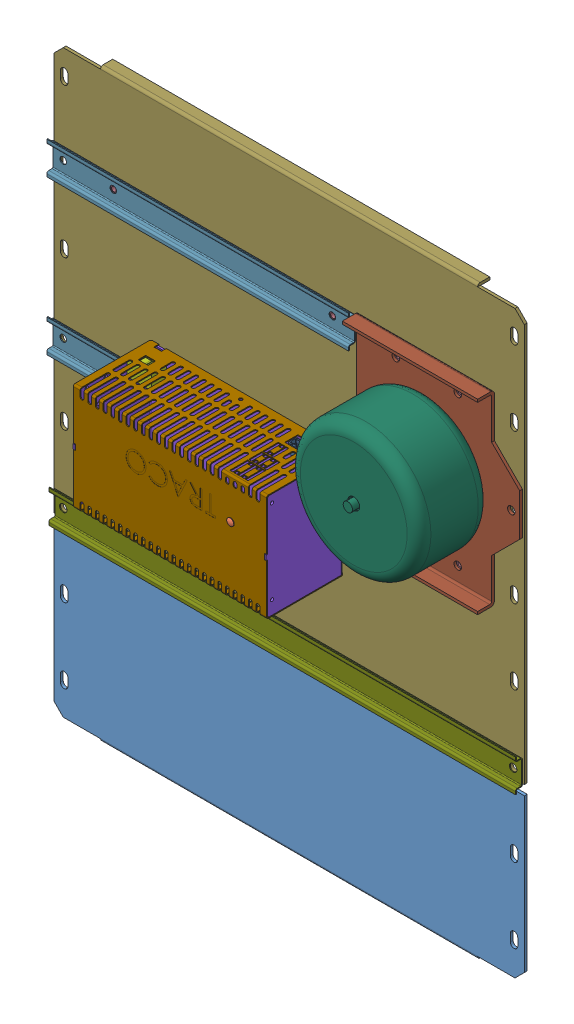
SolidWorks assembly Power Box, configuration Default. Lengths in mm.
Overall size (526 626.85 138).
88 component instances, 24 part files, 3 mates.
Components (placement in the parent):
- PowerBoxBasePlate-2: PowerBoxBasePlate [Default] at (319.6604 211.3465 -51.9675) size (502 176.85 120)
- PA_Components-1: PA_Components [Default] at (34.025 -36.9384 -7.7233) size (525 442.27 138)
  - TRACO_EX_F-1: TRACO_EX_F [Default] at (47.65 -1.49 0) size (207.01 120.7 94.32)
    - 21500011-LENS_EX_F-1: 21500011-LENS_EX_F [Default] at (49.5 13.9 49.6718) x (-0.95952 -0.28164 0) z (-0.28164 0.95952 0) size (7.96 10.08 7.72)
    - 24300124-HOOK_EX_F-1: 24300124-HOOK_EX_F [Default] at (-66.1187 -53.5557 -33.7442) x (0 0 -1) z (0 1 0) size (10 25 60.5)
    - 24300124-HOOK_EX_F-2: 24300124-HOOK_EX_F [Default] at (63.8852 -53.5591 -33.75) x (0 0 -1) z (0 1 0) size (10 25 60.5)
    - 24300137-LATCH_EX_F-1: 24300137-LATCH_EX_F [Default] at (-80.0193 -38.9758 -38.75) x (-1 0 0) z (0 1 0) size (18.25 6.5 48.45)
    - 24300137-LATCH_EX_F-2: 24300137-LATCH_EX_F [Default] at (49.9894 -39.1721 -38.75) x (-1 0 0) z (0 1 0) size (18.25 6.5 48.45)
    - 24500067-SCREW_EX_F-1: 24500067-SCREW_EX_F [Default] at (49.9894 -0.0604 -33.75) x (0.990725 0.135882 0) z (0 0 1) size (8.39 8.11 13.1)
    - 24500067-SCREW_EX_F-2: 24500067-SCREW_EX_F [Default] at (-80.0193 0.1359 -33.75) x (0.990725 0.135882 0) z (0 0 1) size (8.39 8.11 13.1)
    - 23500089-CONNECTOR_EX_F-1: 23500089-CONNECTOR_EX_F [Default] at (-101.43 -45.3069 -16.6442) x (0 -1 0) z (-1 0 0) size (12 12.13 22.86)
    - 23300011-SWITCH_EX_F-1: 23300011-SWITCH_EX_F [Default] at (-102.0205 48.0548 -10.3662) x (-1 0 0) z (0 0 1) size (26.2 16.5 16.5)
    - 24600076-CHASSIS_EX_F-1: 24600076-CHASSIS_EX_F [Default] at (-15.0146 -0.0029 0.0058) x (-1 0 0) z (0 0 -1) size (207 112.6 83.1)
    - 24600075-HOOD_EX_F-1: 24600075-HOOD_EX_F [Default] at (-15.5 0 11.86) x (0 -1 0) z (0 0 1) size (114.6 207 83)
    - 23500094-CONNECTOR_EX_F-1: 23500094-CONNECTOR_EX_F [Default] at (71.6613 45.2988 -16.6481) x (0 1 0) z (1 0 0) size (12 12.13 22.32)
  - ToroidPlate-1: ToroidPlate [Default] at (-36.0063 51.5246 -172.2767) size (175 200 18)
  - PABasePlate-1: PABasePlate [Default] at (285.6354 248.2849 -44.2442) size (525 442.27 138)
    - PA_Plate_F-1: PA_Plate_F [Default] at origin size (523 442.27 138)
    - INSERT M6_EX_F-1: INSERT M6_EX_F [Default] at (-173.625 -84.332 3) x (0.866025 -0.5 0) z (-0.5 -0.866025 0) size (10 12.4 10.93)
    - INSERT M6_EX_F-2: INSERT M6_EX_F [Default] at (-37.35 -86.822 3) x (0.866025 -0.5 0) z (-0.5 -0.866025 0) size (10 12.4 10.93)
    - INSERT M6_EX_F-3: INSERT M6_EX_F [Default] at (-408.325 -249.332 3) x (0.866025 -0.5 0) z (-0.5 -0.866025 0) size (10 12.4 10.93)
    - INSERT M6_EX_F-4: INSERT M6_EX_F [Default] at (-408.325 -84.332 3) x (-0.866025 0.5 0) z (0.5 0.866025 0) size (10 12.4 10.93)
    - INSERT M6_EX_F-5: INSERT M6_EX_F [Default] at (-173.625 -249.332 3) x (0.866025 -0.5 0) z (-0.5 -0.866025 0) size (10 12.4 10.93)
    - INSERT M6_EX_F-6: INSERT M6_EX_F [Default] at (-103.65 -86.822 3) x (0.866025 -0.5 0) z (-0.5 -0.866025 0) size (10 12.4 10.93)
    - INSERT M6_EX_F-7: INSERT M6_EX_F [Default] at (-37.35 -246.842 3) x (0.866025 -0.5 0) z (-0.5 -0.866025 0) size (10 12.4 10.93)
    - INSERT M6_EX_F-8: INSERT M6_EX_F [Default] at (-103.65 -246.842 3) x (0.866025 -0.5 0) z (-0.5 -0.866025 0) size (10 12.4 10.93)
    - INSERT M6_EX_F-10: INSERT M6_EX_F [Default] at (-290.975 -84.332 3) x (0.866025 -0.5 0) z (-0.5 -0.866025 0) size (10 12.4 10.93)
    - INSERT M6_EX_F-12: INSERT M6_EX_F [Default] at (-290.975 -249.332 3) x (0.866025 -0.5 0) z (-0.5 -0.866025 0) size (10 12.4 10.93)
    - CLS-M4-0-PennEngineering-01-13-2017_F-13: CLS-M4-0-PennEngineering-01-13-2017_F [Default] at (-493.23 -161.4004 115.3) x (-1 0 0) z (0 0 1) size (2.77 7.87 7.87)
    - CLS-M4-0-PennEngineering-01-13-2017_F-12: CLS-M4-0-PennEngineering-01-13-2017_F [Default] at (-493.23 -302.6752 115.3) x (-1 0 0) z (0 0 1) size (2.77 7.87 7.87)
    - CLS-M4-0-PennEngineering-01-13-2017_F-10: CLS-M4-0-PennEngineering-01-13-2017_F [Default] at (-493.23 -161.4004 58.15) x (-1 0 0) z (0 0 1) size (2.77 7.87 7.87)
    - CLS-M4-0-PennEngineering-01-13-2017_F-9: CLS-M4-0-PennEngineering-01-13-2017_F [Default] at (-493.23 -302.6752 58.15) x (-1 0 0) z (0 0 1) size (2.77 7.87 7.87)
    - CLS-M4-0-PennEngineering-01-13-2017_F-14: CLS-M4-0-PennEngineering-01-13-2017_F [Default] at (-493.23 11.4752 58.15) x (-1 0 0) z (0 0 1) size (2.77 7.87 7.87)
    - CLS-M4-0-PennEngineering-01-13-2017_F-16: CLS-M4-0-PennEngineering-01-13-2017_F [Default] at (-493.23 11.4752 115.3) x (-1 0 0) z (0 0 1) size (2.77 7.87 7.87)
    - CLS-M4-0-PennEngineering-01-13-2017_F-11: CLS-M4-0-PennEngineering-01-13-2017_F [Default] at (-493.23 -129.7996 115.3) x (-1 0 0) z (0 0 1) size (2.77 7.87 7.87)
    - CLS-M4-0-PennEngineering-01-13-2017_F-15: CLS-M4-0-PennEngineering-01-13-2017_F [Default] at (-493.23 -129.7996 58.15) x (-1 0 0) z (0 0 1) size (2.77 7.87 7.87)
  - DIN_SHORT_EX_F-1: DIN_SHORT_EX_F [Default] at (299.0854 -1.047 -41.2442) x (-1 0 0) z (0 1 0) size (323 7.5 35)
  - DIN_SHORT_EX_F-2: DIN_SHORT_EX_F [Default] at (299.0854 163.953 -41.2442) x (-1 0 0) z (0 1 0) size (323 7.5 35)
  - Toroid2_F-1: Toroid2_F [Default] at (-71.2443 268.0211 39.9558) x (-0.653017 -0.757343 0) z (0 0 -1) size (139.7 139.7 88.9)
  - DOUBLE-1: DOUBLE [Default] at (99.7354 120.553 32.1912) size (36.74 93.9 72.67)
    - SB100443_S_ASM_Next assembly relationship#COQUE_PRINCIPALE_2P;COQUE_PRINCIPALE_2P-1: SB100443_S_ASM_Next assembly relationship#COQUE_PRINCIPALE_2P;COQUE_PRINCIPALE_2P [Default] at origin size (36.74 84.8 72.67)
    - SB100443_S_ASM_Next assembly relationship#CLIP_2;CLIP_2-1: SB100443_S_ASM_Next assembly relationship#CLIP_2;CLIP_2 [Default] at origin size (17 32.3 5.5)
    - SB100443_S_ASM_Next assembly relationship#CLIP_1;CLIP_1-1: SB100443_S_ASM_Next assembly relationship#CLIP_1;CLIP_1 [Default] at origin size (15.5 30.66 6.39)
    - SB100443_S_ASM_Next assembly relationship#VIS_7_2;VIS_7_2-1: SB100443_S_ASM_Next assembly relationship#VIS_7_2;VIS_7_2 [Default] at origin size (7.2 7.2 2)
    - SB100443_S_ASM_Next assembly relationship#VIS_7_2;VIS_7_2_2-1: SB100443_S_ASM_Next assembly relationship#VIS_7_2;VIS_7_2_2 [Default] at origin size (7.2 7.2 2)
    - SB100443_S_ASM_Next assembly relationship#VIS_7_2;VIS_7_2_3-1: SB100443_S_ASM_Next assembly relationship#VIS_7_2;VIS_7_2_3 [Default] at origin size (7.2 7.2 2)
    - SB100443_S_ASM_Next assembly relationship#VIS_7_2;VIS_7_2_4-1: SB100443_S_ASM_Next assembly relationship#VIS_7_2;VIS_7_2_4 [Default] at origin size (7.2 7.2 2)
  - DOUBLE-2: DOUBLE [Default] at (61.6354 120.553 32.1912) size (36.74 93.9 72.67)
    - SB100443_S_ASM_Next assembly relationship#COQUE_PRINCIPALE_2P;COQUE_PRINCIPALE_2P-1: SB100443_S_ASM_Next assembly relationship#COQUE_PRINCIPALE_2P;COQUE_PRINCIPALE_2P [Default] at origin size (36.74 84.8 72.67)
    - SB100443_S_ASM_Next assembly relationship#CLIP_2;CLIP_2-1: SB100443_S_ASM_Next assembly relationship#CLIP_2;CLIP_2 [Default] at origin size (17 32.3 5.5)
    - SB100443_S_ASM_Next assembly relationship#CLIP_1;CLIP_1-1: SB100443_S_ASM_Next assembly relationship#CLIP_1;CLIP_1 [Default] at origin size (15.5 30.66 6.39)
    - SB100443_S_ASM_Next assembly relationship#VIS_7_2;VIS_7_2-1: SB100443_S_ASM_Next assembly relationship#VIS_7_2;VIS_7_2 [Default] at origin size (7.2 7.2 2)
    - SB100443_S_ASM_Next assembly relationship#VIS_7_2;VIS_7_2_2-1: SB100443_S_ASM_Next assembly relationship#VIS_7_2;VIS_7_2_2 [Default] at origin size (7.2 7.2 2)
    - SB100443_S_ASM_Next assembly relationship#VIS_7_2;VIS_7_2_3-1: SB100443_S_ASM_Next assembly relationship#VIS_7_2;VIS_7_2_3 [Default] at origin size (7.2 7.2 2)
    - SB100443_S_ASM_Next assembly relationship#VIS_7_2;VIS_7_2_4-1: SB100443_S_ASM_Next assembly relationship#VIS_7_2;VIS_7_2_4 [Default] at origin size (7.2 7.2 2)
  - DOUBLE-3: DOUBLE [Default] at (23.5354 120.553 32.1912) size (36.74 93.9 72.67)
    - SB100443_S_ASM_Next assembly relationship#COQUE_PRINCIPALE_2P;COQUE_PRINCIPALE_2P-1: SB100443_S_ASM_Next assembly relationship#COQUE_PRINCIPALE_2P;COQUE_PRINCIPALE_2P [Default] at origin size (36.74 84.8 72.67)
    - SB100443_S_ASM_Next assembly relationship#CLIP_2;CLIP_2-1: SB100443_S_ASM_Next assembly relationship#CLIP_2;CLIP_2 [Default] at origin size (17 32.3 5.5)
    - SB100443_S_ASM_Next assembly relationship#CLIP_1;CLIP_1-1: SB100443_S_ASM_Next assembly relationship#CLIP_1;CLIP_1 [Default] at origin size (15.5 30.66 6.39)
    - SB100443_S_ASM_Next assembly relationship#VIS_7_2;VIS_7_2-1: SB100443_S_ASM_Next assembly relationship#VIS_7_2;VIS_7_2 [Default] at origin size (7.2 7.2 2)
    - SB100443_S_ASM_Next assembly relationship#VIS_7_2;VIS_7_2_2-1: SB100443_S_ASM_Next assembly relationship#VIS_7_2;VIS_7_2_2 [Default] at origin size (7.2 7.2 2)
    - SB100443_S_ASM_Next assembly relationship#VIS_7_2;VIS_7_2_3-1: SB100443_S_ASM_Next assembly relationship#VIS_7_2;VIS_7_2_3 [Default] at origin size (7.2 7.2 2)
    - SB100443_S_ASM_Next assembly relationship#VIS_7_2;VIS_7_2_4-1: SB100443_S_ASM_Next assembly relationship#VIS_7_2;VIS_7_2_4 [Default] at origin size (7.2 7.2 2)
  - DOUBLE-4: DOUBLE [Default] at (-14.5646 120.553 32.1912) size (36.74 93.9 72.67)
    - SB100443_S_ASM_Next assembly relationship#COQUE_PRINCIPALE_2P;COQUE_PRINCIPALE_2P-1: SB100443_S_ASM_Next assembly relationship#COQUE_PRINCIPALE_2P;COQUE_PRINCIPALE_2P [Default] at origin size (36.74 84.8 72.67)
    - SB100443_S_ASM_Next assembly relationship#CLIP_2;CLIP_2-1: SB100443_S_ASM_Next assembly relationship#CLIP_2;CLIP_2 [Default] at origin size (17 32.3 5.5)
    - SB100443_S_ASM_Next assembly relationship#CLIP_1;CLIP_1-1: SB100443_S_ASM_Next assembly relationship#CLIP_1;CLIP_1 [Default] at origin size (15.5 30.66 6.39)
    - SB100443_S_ASM_Next assembly relationship#VIS_7_2;VIS_7_2-1: SB100443_S_ASM_Next assembly relationship#VIS_7_2;VIS_7_2 [Default] at origin size (7.2 7.2 2)
    - SB100443_S_ASM_Next assembly relationship#VIS_7_2;VIS_7_2_2-1: SB100443_S_ASM_Next assembly relationship#VIS_7_2;VIS_7_2_2 [Default] at origin size (7.2 7.2 2)
    - SB100443_S_ASM_Next assembly relationship#VIS_7_2;VIS_7_2_3-1: SB100443_S_ASM_Next assembly relationship#VIS_7_2;VIS_7_2_3 [Default] at origin size (7.2 7.2 2)
    - SB100443_S_ASM_Next assembly relationship#VIS_7_2;VIS_7_2_4-1: SB100443_S_ASM_Next assembly relationship#VIS_7_2;VIS_7_2_4 [Default] at origin size (7.2 7.2 2)
  - DOUBLE-5: DOUBLE [Default] at (-52.6646 120.553 32.1912) size (36.74 93.9 72.67)
    - SB100443_S_ASM_Next assembly relationship#COQUE_PRINCIPALE_2P;COQUE_PRINCIPALE_2P-1: SB100443_S_ASM_Next assembly relationship#COQUE_PRINCIPALE_2P;COQUE_PRINCIPALE_2P [Default] at origin size (36.74 84.8 72.67)
    - SB100443_S_ASM_Next assembly relationship#CLIP_2;CLIP_2-1: SB100443_S_ASM_Next assembly relationship#CLIP_2;CLIP_2 [Default] at origin size (17 32.3 5.5)
    - SB100443_S_ASM_Next assembly relationship#CLIP_1;CLIP_1-1: SB100443_S_ASM_Next assembly relationship#CLIP_1;CLIP_1 [Default] at origin size (15.5 30.66 6.39)
    - SB100443_S_ASM_Next assembly relationship#VIS_7_2;VIS_7_2-1: SB100443_S_ASM_Next assembly relationship#VIS_7_2;VIS_7_2 [Default] at origin size (7.2 7.2 2)
    - SB100443_S_ASM_Next assembly relationship#VIS_7_2;VIS_7_2_2-1: SB100443_S_ASM_Next assembly relationship#VIS_7_2;VIS_7_2_2 [Default] at origin size (7.2 7.2 2)
    - SB100443_S_ASM_Next assembly relationship#VIS_7_2;VIS_7_2_3-1: SB100443_S_ASM_Next assembly relationship#VIS_7_2;VIS_7_2_3 [Default] at origin size (7.2 7.2 2)
    - SB100443_S_ASM_Next assembly relationship#VIS_7_2;VIS_7_2_4-1: SB100443_S_ASM_Next assembly relationship#VIS_7_2;VIS_7_2_4 [Default] at origin size (7.2 7.2 2)
  - DOUBLE-6: DOUBLE [Default] at (-90.7646 120.553 32.1912) size (36.74 93.9 72.67)
    - SB100443_S_ASM_Next assembly relationship#COQUE_PRINCIPALE_2P;COQUE_PRINCIPALE_2P-1: SB100443_S_ASM_Next assembly relationship#COQUE_PRINCIPALE_2P;COQUE_PRINCIPALE_2P [Default] at origin size (36.74 84.8 72.67)
    - SB100443_S_ASM_Next assembly relationship#CLIP_2;CLIP_2-1: SB100443_S_ASM_Next assembly relationship#CLIP_2;CLIP_2 [Default] at origin size (17 32.3 5.5)
    - SB100443_S_ASM_Next assembly relationship#CLIP_1;CLIP_1-1: SB100443_S_ASM_Next assembly relationship#CLIP_1;CLIP_1 [Default] at origin size (15.5 30.66 6.39)
    - SB100443_S_ASM_Next assembly relationship#VIS_7_2;VIS_7_2-1: SB100443_S_ASM_Next assembly relationship#VIS_7_2;VIS_7_2 [Default] at origin size (7.2 7.2 2)
    - SB100443_S_ASM_Next assembly relationship#VIS_7_2;VIS_7_2_2-1: SB100443_S_ASM_Next assembly relationship#VIS_7_2;VIS_7_2_2 [Default] at origin size (7.2 7.2 2)
    - SB100443_S_ASM_Next assembly relationship#VIS_7_2;VIS_7_2_3-1: SB100443_S_ASM_Next assembly relationship#VIS_7_2;VIS_7_2_3 [Default] at origin size (7.2 7.2 2)
    - SB100443_S_ASM_Next assembly relationship#VIS_7_2;VIS_7_2_4-1: SB100443_S_ASM_Next assembly relationship#VIS_7_2;VIS_7_2_4 [Default] at origin size (7.2 7.2 2)
- DIN_LONGPWBX-1: DIN_LONGPWBX [Default] at (348.6604 -195.2264 -48.9675) x (-1 0 0) z (0 1 0) size (500 7.5 35)
Mates (geometry in assembly coordinates):
- Coincident1: coincident anti-aligned: plane of PA_Components-1/PABasePlate-1/PA_Plate_F-1 through (-145.3396 -357.6535 -48.9675) normal (0 0 1); plane of DIN_LONGPWBX-1 through (348.6604 -206.7264 -48.9675) normal (0 0 -1)
- Width1: width anti-aligned: plane of DIN_LONGPWBX-1 through (-151.3396 -195.2264 -46.3376) normal (-1 0 0); plane of DIN_LONGPWBX-1 through (348.6604 -195.2264 -46.3376) normal (1 0 0); plane of PowerBoxBasePlate-2 through (350.6604 210.3465 -48.9675) normal (1 0 0); plane of PowerBoxBasePlate-2 through (-153.3396 210.3465 -48.9675) normal (-1 0 0)
- Coincident6: coincident aligned: plane of PA_Components-1/PABasePlate-1/PA_Plate_F-1 through (290.6604 -208.7264 14.9638) normal (0 -1 0); plane of DIN_LONGPWBX-1 through (348.6604 -208.7264 -43.4675) normal (0 -1 0)
